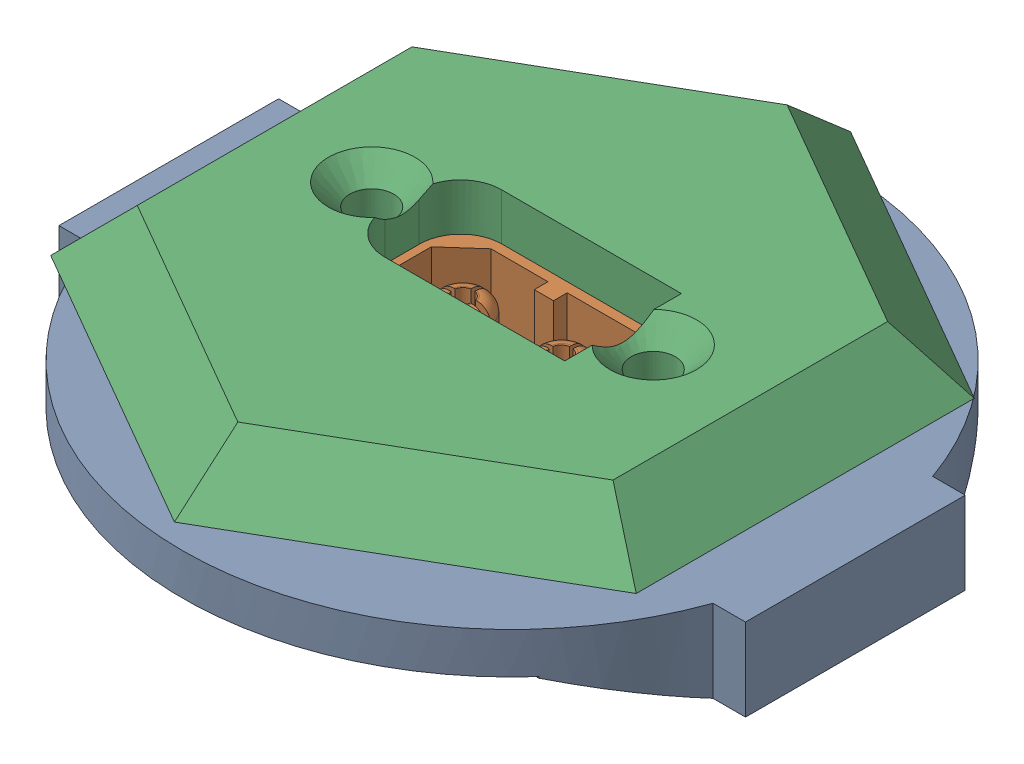
SolidWorks assembly R7_GS_112C_POWER_CONNECTOR, configuration Domyślna. Lengths in mm.
Overall size (50 19.99 49.24).
3 component instances, 3 part files, 0 mates.
Components (placement in the parent):
- R7_GS_112C2_HOLDER-2: R7_GS_112C2_HOLDER [Domyślna] at (-2.1206 -0.3735 12) size (50 6 48)
- R7_GS_112C1_XT60_MALE-2: R7_GS_112C1_XT60_MALE [Domyślna] at (-2.072 5.629 12.0321) x (1 0 0) z (0 1 0) size (27.18 12 16.6)
- R7_GS_112C3_HOLDER_FRONT-1: R7_GS_112C3_HOLDER_FRONT [Domyślna] at (-2.0754 7.77 12.0146) size (42.64 6.25 49.24)
